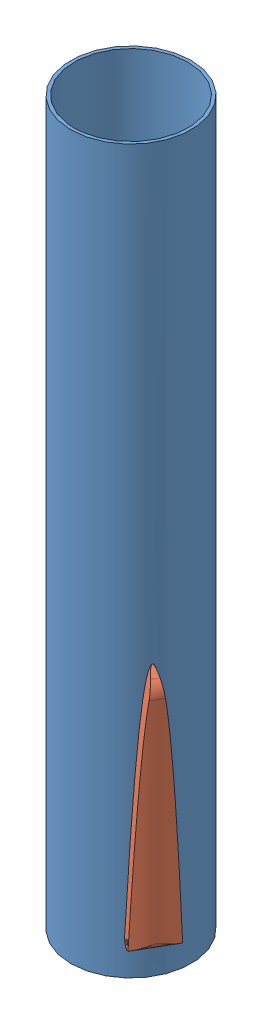
SolidWorks assembly phi, configuration Default. Lengths in mm.
Overall size (86.6 457.2 76.28).
2 component instances, 2 part files, 2 mates.
Components (placement in the parent):
- airframe-1: airframe [Default] at (126.5458 83.5384 479.5599) size (76.2 457.2 76.2)
- leg-1: leg [Default] at (165.5371 103.5097 488.1401) x (0.008609 0.999951 0.00497) z (0.5 0 -0.866025) size (163.04 27.95 28.16)
Mates (geometry in assembly coordinates):
- Coincident1: coincident anti-aligned: plane of airframe-1 through (170.6661 134.3384 507.2325) normal (0.5 0 -0.866025); plane of leg-1 through (158.5521 103.5097 500.2385) normal (-0.5 0 0.866025)
- Tangent2: tangent anti-aligned: cylinder of airframe-1 through (126.5458 540.7384 479.5599) axis (0 -1 0) radius 38.1; cylinder of leg-1 through (155.282 107.7652 514.5165) axis (0.5 0 -0.866025) radius 4.2645
